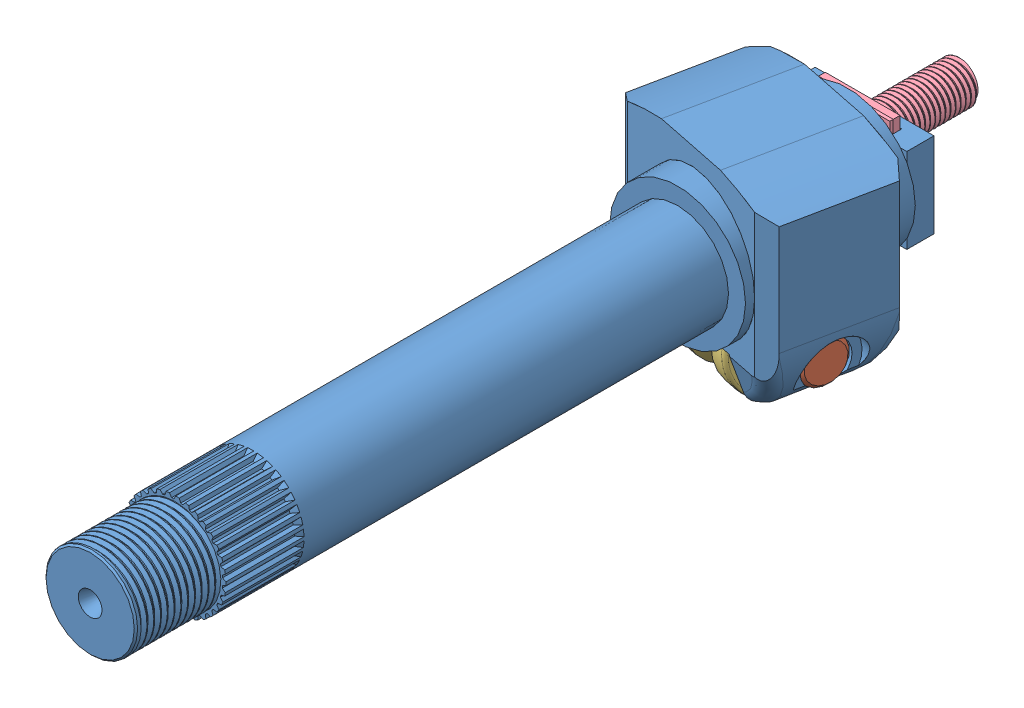
SolidWorks assembly подсборка вала, configuration По умолчанию. Lengths in mm.
Overall size (64.74 65 256.63).
4 component instances, 4 part files, 7 mates.
Components (placement in the parent):
- вал-1: вал [По умолчанию] at (113.315 142.2512 142.0381) size (64.74 60.51 231)
- штивт для вала-1: штивт для вала [По умолчанию] at (136.8301 118.7512 71.8381) x (0.04 0.979796 -0.195959) z (-0.195959 0.2 0.96) size (13 48 13)
- ролик для вала-1: ролик для вала [По умолчанию] at (106.8687 118.7512 65.7223) x (0.979796 0 0.2) z (-0.2 0 0.979796) size (29 33 33)
- резьба под вал-1: резьба под вал [По умолчанию] at (113.315 147.4612 9.0381) x (0 0 1) z (1 0 0) size (31.63 22 22)
Mates (geometry in assembly coordinates):
- Концентричный3: concentric anti-aligned: cylinder of вал-1 through (158.3857 118.7512 76.2381) axis (-0.979796 0 -0.2) radius 6.5; cylinder of штивт для вала-1 through (89.7999 118.7512 62.2381) axis (0.979796 0 0.2) radius 6.5
- Совпадение1: coincident aligned: plane of вал-1 through (89.7999 118.7512 62.2381) normal (-0.979796 0 -0.2); plane of штивт для вала-1 through (89.7999 118.7512 62.2381) normal (-0.979796 0 -0.2)
- Концентричный4: concentric anti-aligned: cylinder of штивт для вала-1 through (89.7999 118.7512 62.2381) axis (0.979796 0 0.2) radius 6.5; cylinder of ролик для вала-1 through (94.6186 118.7512 63.2218) axis (-0.979796 0 -0.2) radius 6.5
- Совпадение2: coincident anti-aligned: plane of ролик для вала-1 through (100.408 118.7512 57.7695) normal (-0.979796 0 -0.2); plane of вал-1 through (99.108 122.2512 64.1381) normal (0.979796 0 0.2)
- Совпадение3: coincident anti-aligned: plane of вал-1 through (102.315 162.2512 37.0381) normal (1 0 0); plane of резьба под вал-1 through (102.315 156.3296 40.0381) normal (-1 0 0)
- Совпадение4: coincident anti-aligned: plane of вал-1 through (102.315 162.2512 37.0381) normal (0 0 1); plane of резьба под вал-1 through (113.315 145.3296 37.0381) normal (0 0 -1)
- Расстояние3: distance = 6.71 mm aligned: plane of резьба под вал-1 through (102.315 136.4612 40.0381) normal (0 -1 0); plane of вал-1 through (95.815 129.7512 34.0381) normal (0 -1 0)
